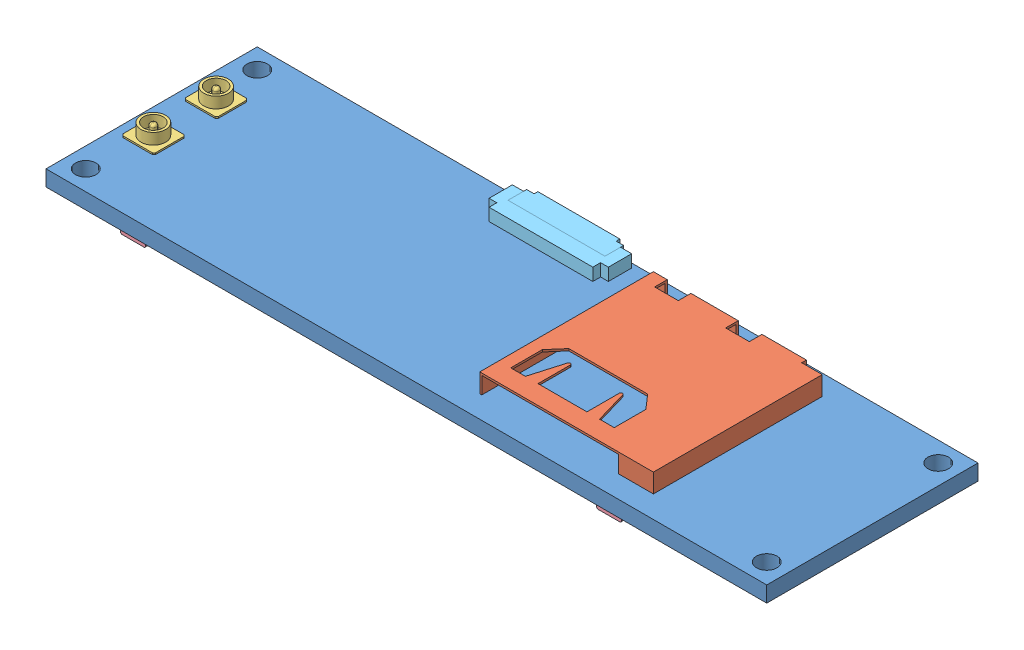
SolidWorks assembly BOARD, Overo Air, configuration Default. Lengths in mm.
Overall size (58 3.99 17.2).
7 component instances, 5 part files, 0 mates.
Components (placement in the parent):
- OveroAir-Fire-MOTHERBOARD-1: OveroAir-Fire-MOTHERBOARD [Default] at origin size (58 1.27 17)
- MSDslot-1: MSDslot [Default] at (11.114 0.635 -0.263) size (13.97 1.52 13.97)
- u.FLCon-1: u.FLCon [Default] at (-26.9 0.762 -3.09) size (2.63 1.02 2.54)
- u.FLCon-2: u.FLCon [Default] at (-26.9 0.762 1.96) size (2.63 1.02 2.54)
- AVX5602-70pinmale-1: AVX5602-70pinmale [Default] at (-22.95 -0.635 0) x (-1 0 0) z (0 0 1) size (2 1.2 15.1)
- AVX5602-70pinmale-2: AVX5602-70pinmale [Default] at (15.35 -0.635 0) x (-1 0 0) z (0 0 1) size (2 1.2 15.1)
- FH26-27S-1: FH26-27S [Default] at (-3.32 0.635 -6.9) x (-1 0 0) z (0 0 -1) size (9.6 1 3.05)
